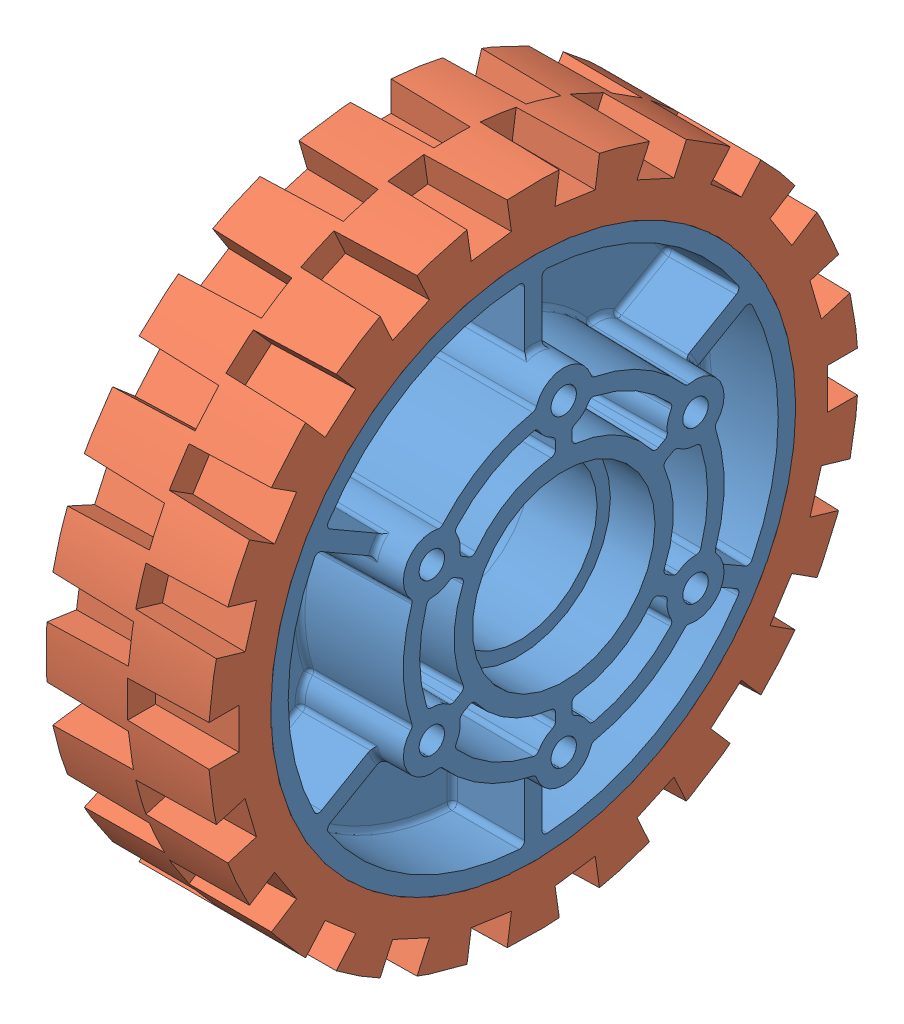
SolidWorks assembly 4 in HiGrip Wheel, configuration Default. Lengths in mm.
Overall size (34.92 101.6 101.6).
2 component instances, 2 part files, 1 mates.
Components (placement in the parent):
- 4in 2013 Hub-1: 4in 2013 Hub [Default] at (-8.0517 2.5236 2.5343) size (34.92 82.55 82.55)
- 4 in tread-1: 4 in tread [Default] at (-8.0517 2.5236 2.5343) size (25.4 101.6 101.6)
Mates (geometry in assembly coordinates):
- Coincident1: coincident aligned: circle of 4in 2013 Hub-1; circle of 4 in tread-1
